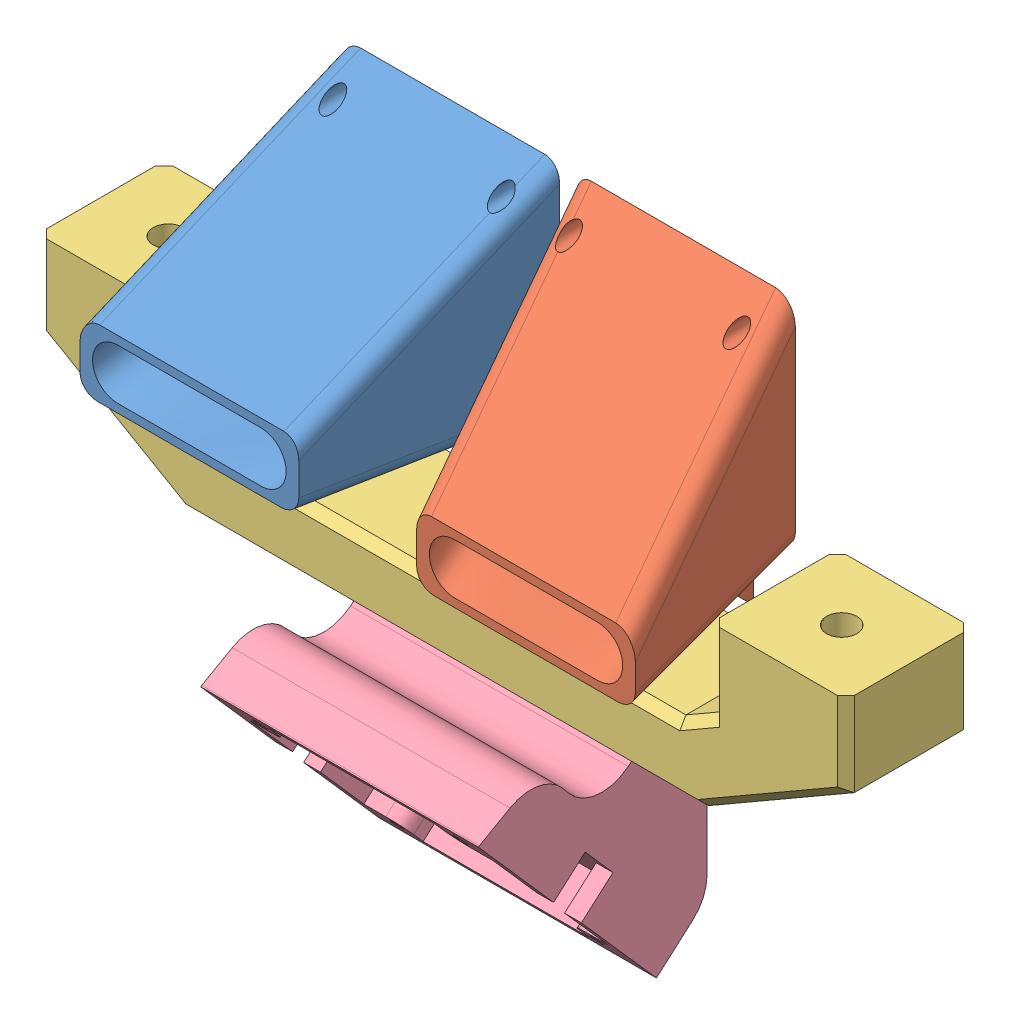
SolidWorks assembly extras-plate, configuration Default. Lengths in mm.
Overall size (96 72.11 35.37).
4 component instances, 4 part files, 14 mates.
Components (placement in the parent):
- extrudate-fan-right-1: extrudate-fan-right [Default] at (-14 36.3295 0) x (1 0 0) z (0 -1 0) size (32 25.01 33.29)
- extrudate-fan-left-2: extrudate-fan-left [Default] at (14 36.3295 0) x (1 0 0) z (0 -1 0) size (32 25.01 33.29)
- door-handle-1: door-handle [Default] at (202.375 -137.4202 109.1346) x (0 0.5 0.866025) z (0 -0.866025 0.5) size (22.49 96 24.32)
- Camera-Mount-1: Camera-Mount [Default] at (-16.5 -17.4963 0) x (0 1 0) z (0 0 -1) size (26.84 33 27.15)
Mates (geometry in assembly coordinates):
- Coincident1: coincident anti-aligned: plane of door-handle-1 through (-48 6.0366 0) normal (0 0 -1); plane of assembly through (0 0 0) normal (0 0 1)
- Coincident3: coincident anti-aligned: plane of extrudate-fan-left-2 through (14 36.3295 0) normal (0 0 -1); plane of assembly through (0 0 0) normal (0 0 1)
- Parallel1: parallel aligned: plane of door-handle-1 through (48 6.0366 0) normal (1 0 0); plane of assembly through (0 0 0) normal (1 0 0)
- Parallel2: parallel aligned: plane of extrudate-fan-left-2; plane of assembly through (0 0 0) normal (1 0 0)
- Parallel3: parallel aligned: plane of extrudate-fan-right-1; plane of assembly through (0 0 0) normal (1 0 0)
- Distance3: distance = 2 mm anti-aligned: cylinder of Camera-Mount-1 through (16.5 -0.9634 3.4416) axis (-1 0 0) radius 5; plane of door-handle-1 through (202.375 6.0366 109.1346) normal (0 -1 0)
- Coincident11: coincident: moEndPointRef_w of Camera-Mount-1; plane of assembly
- Coincident12: coincident: moEndPointRef_w of door-handle-1; plane of assembly
- Distance4: distance = 18 mm: cylinder of extrudate-fan-left-2 through (10 35.7618 -13.5745) axis (0 -0.707107 0.707107) radius 1; cylinder of extrudate-fan-right-1 through (-10 35.7618 -13.5745) axis (0 -0.707107 0.707107) radius 1
- Distance5: distance = 2 mm anti-aligned: plane of extrudate-fan-left-2 through (14 16.0366 0) normal (0 -1 0); plane of door-handle-1 through (-32 14.0366 232.9342) normal (0 1 0)
- Coincident14: coincident anti-aligned: plane of extrudate-fan-right-1 through (-14 36.3295 0) normal (0 0 -1); plane of assembly through (0 0 0) normal (0 0 1)
- Coincident15: coincident aligned: plane of extrudate-fan-right-1 through (-14 16.0366 0) normal (0 -1 0); plane of extrudate-fan-left-2 through (14 16.0366 0) normal (0 -1 0)
- Distance6: distance = 1 mm: plane of assembly through (0 0 0) normal (1 0 0); line of extrudate-fan-left-2 through (1 47.1721 0) axis (0 -1 0)
- Coincident18: coincident anti-aligned: plane of Camera-Mount-1 through (16.5 -17.4963 0) normal (0 0 -1); plane of assembly through (0 0 0) normal (0 0 1)
